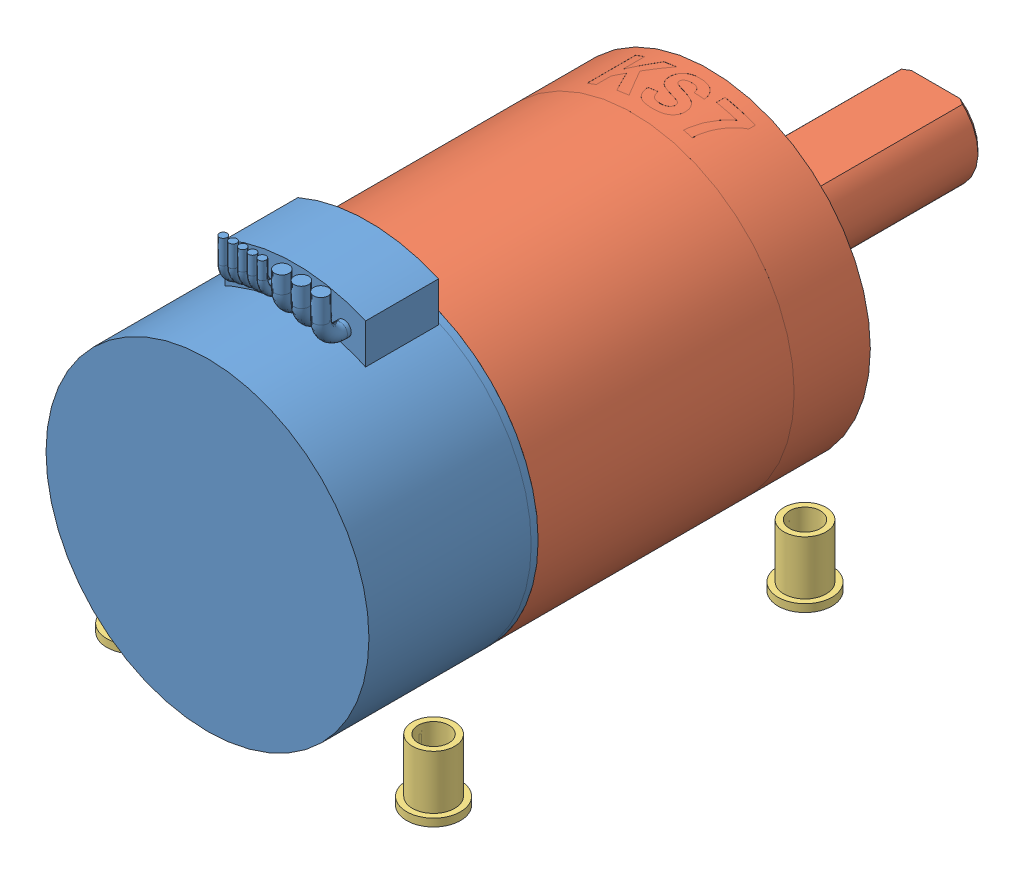
SolidWorks assembly Assemblage moteur-cache-insert Total, configuration Défaut. Lengths in mm.
Overall size (48.69 52 94.7).
7 component instances, 3 part files, 11 mates.
Components (placement in the parent):
- Assemblage Moteur-réducteur Faulhaber-1: Assemblage Moteur-réducteur Faulhaber [Défaut] at (10.0724 13.6207 164.5) x (1 0 0) z (0 0 -1) size (42 48.5 94.7)
  - 4221G_BXTH _ moteur-1: 4221G_BXTH _ moteur [Défaut] at (-4.2788 3.5509 53) size (42 48.5 35)
  - 42gpt-2stage_standard+KSx _ reducteur-1: 42gpt-2stage_standard+KSx _ reducteur [Défaut] at (-138.2788 3.5509 53) size (42 42.04 72.7)
- Insert M4-1: Insert M4 [Défaut] at (-13.7064 -14.4301 123.6) x (1 0 0) z (0 1 0) size (7 7 8)
- Insert M4-2: Insert M4 [Défaut] at (25.2936 -14.4301 123.6) x (-0.837169 0 -0.546944) z (0 1 0) size (7 7 8)
- Insert M4-3: Insert M4 [Défaut] at (25.2936 -14.4301 75.3) x (1 0 0) z (0 1 0) size (7 7 8)
- Insert M4-4: Insert M4 [Défaut] at (-13.7064 -14.4301 75.3) x (-0.837169 0 -0.546944) z (0 1 0) size (7 7 8)
Mates (geometry in assembly coordinates):
- Coaxiale1: concentric aligned: circle of Cache moteur_V2-1; circle of Insert M4-1
- Coaxiale2: concentric aligned: circle of Cache moteur_V2-1; circle of Insert M4-2
- Coaxiale3: concentric aligned: circle of Cache moteur_V2-1; circle of Insert M4-3
- Coaxiale4: concentric aligned: circle of Cache moteur_V2-1; circle of Insert M4-4
- Coïncidente11: coincident aligned: plane of Cache moteur_V2-1 through (5.7936 -14.4301 133.6) normal (0 -1 0); plane of Insert M4-1 through (-13.7064 -14.4301 123.6) normal (0 -1 0)
- Coïncidente12: coincident aligned: plane of Cache moteur_V2-1 through (5.7936 -14.4301 133.6) normal (0 -1 0); plane of Insert M4-2 through (25.2936 -14.4301 123.6) normal (0 -1 0)
- Coïncidente13: coincident aligned: plane of Cache moteur_V2-1 through (5.7936 -14.4301 133.6) normal (0 -1 0); plane of Insert M4-3 through (25.2936 -14.4301 75.3) normal (0 -1 0)
- Coïncidente14: coincident aligned: plane of Cache moteur_V2-1 through (5.7936 -14.4301 133.6) normal (0 -1 0); plane of Insert M4-4 through (-13.7064 -14.4301 75.3) normal (0 -1 0)
- Coaxiale5: concentric anti-aligned: circle of Cache moteur_V2-1; circle of Assemblage Moteur-réducteur Faulhaber-1/42gpt-2stage_standard+KSx _ reducteur-1
- Coïncidente15: coincident anti-aligned: plane of Cache moteur_V2-1 through (5.7936 10.0699 68.3) normal (0 0 1); plane of Assemblage Moteur-réducteur Faulhaber-1/42gpt-2stage_standard+KSx _ reducteur-1 through (5.7936 10.0699 68.3) normal (0 0 -1)
- Coaxiale6: concentric anti-aligned: circle of Cache moteur_V2-1; circle of Assemblage Moteur-réducteur Faulhaber-1/42gpt-2stage_standard+KSx _ reducteur-1
